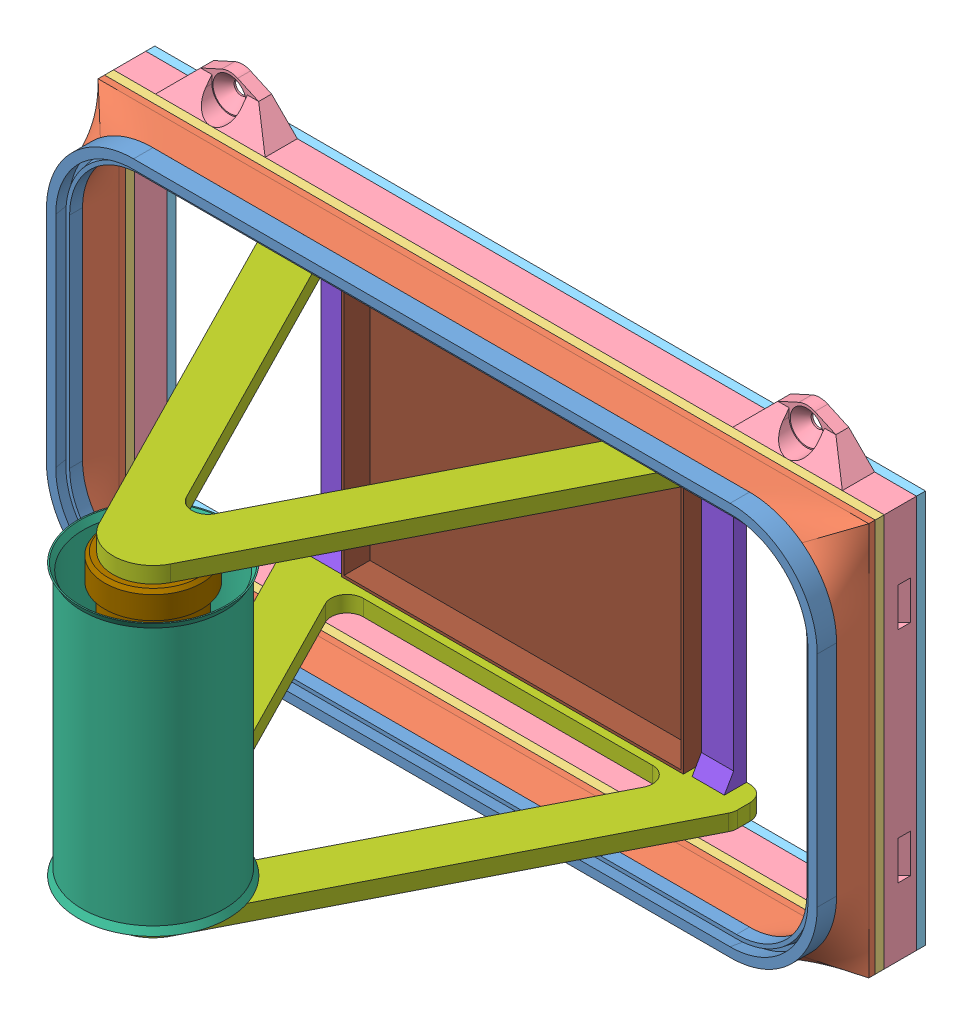
SolidWorks assembly Enclosure Filament Container, configuration Default. Lengths in mm.
Overall size (245.51 145 230).
25 component instances, 17 part files, 28 mates.
Components (placement in the parent):
- Filament Container Extension_v19.step-1: Filament Container Extension_v19.step [Default] at origin size (264.5 145 42.8)
  - Component8.step-1: Component8.step [Default] at origin size (201 111.5 39.6) (hidden)
    - CaseBot.step-1: CaseBot.step [Default] at origin size (180 107 26)
    - Axis.step-1: Axis.step [Default] at origin size (108 100 8)
    - Bearing.step-1: Bearing.step [Default] at origin size (22 7 22) (hidden)
    - Bearing.step-2: Bearing.step [Default] at (0 95 0) size (22 7 22) (hidden)
    - Bearing.step-3: Bearing.step [Default] at (-100 0 0) size (22 7 22) (hidden)
    - Bearing.step-4: Bearing.step [Default] at (-100 95 0) size (22 7 22) (hidden)
    - CaseTop.step-1: CaseTop.step [Default] at origin size (175.2 102.2 2)
  - ContainerLatch.step-1: ContainerLatch.step [Default] at origin size (239 122 6)
  - TopPiece.step-1: TopPiece.step [Default] at origin size (245.51 122 12)
  - Foam1.step-1: Foam1.step [Default] at origin size (239 122 2.8)
  - BottomPiece.step-1: BottomPiece.step [Default] at origin size (245 145 19.3)
  - Foam2.step-1: Foam2.step [Default] at origin size (239 122 2.8)
  - FrontLatch.step-1: FrontLatch.step [Default] at origin size (21.6 12 37.2) (hidden)
  - Spacer.step-1: Spacer.step [Default] at origin size (12 11.5 2.8) (hidden)
- Part48^Enclosure Filament Container-1: Part48^Enclosure Filament Container [Default] x (1 0 0) z (0 1 0) size (220 220 84) (virtual)
- Part49^Enclosure Filament Container-1: Part49^Enclosure Filament Container [Default] x (1 0 0) z (0 1 0) size (140 132.4 50) (virtual)
- Part49^Enclosure Filament Container-3: Part49^Enclosure Filament Container [Default] x (-1 0 0) z (0 -1 0) size (140 132.4 50) (virtual)
- Part52^Enclosure Filament Container-1: Part52^Enclosure Filament Container [Default] at (0 0 -28.6) x (1 0 0) z (0 0 -1) size (10 108 6.9) (virtual)
- Part52^Enclosure Filament Container-2: Part52^Enclosure Filament Container [Default] at (-118 0 -28.6) x (1 0 0) z (0 0 -1) size (10 108 6.9) (virtual)
- Part53^Enclosure Filament Container-1: Part53^Enclosure Filament Container [Default] at (0 45 0) x (-1 0 0) z (0 -1 0) size (30 30 17) (virtual)
- Part53^Enclosure Filament Container-2: Part53^Enclosure Filament Container [Default] at (0 -45 0) x (1 0 0) z (0 1 0) size (30 30 17) (virtual)
- Part54^Enclosure Filament Container-1: Part54^Enclosure Filament Container [Default] x (1 0 0) z (0 1 0) size (16.2 16.2 68) (virtual)
- Part55^Enclosure Filament Container-1: Part55^Enclosure Filament Container [Default] at origin size (106 88 8.6) (virtual)
Mates (geometry in assembly coordinates):
- InPlace1: in place: plane of ? through (0 0 0) normal (0 1 0); plane of ? through (0 0 0) normal (0 1 0); moOrthogonalPlaneRef_w of ? through (0 0 0) normal (0 1 0); plane of ? through (0 0 0) normal (0 0 -1); plane of ? through (0 0 0) normal (0 1 0); plane of ? through (0 0 0) normal (1 0 0); plane of ? through (0 0 0) normal (0 1 0); unknown of ?
- Coincident1: coincident aligned: plane of Filament Container Extension_v19.step-1; plane of Part48^Enclosure Filament Container-1
- Coincident2: coincident aligned: moOrthogonalPlaneRef_w of Filament Container Extension_v19.step-1; plane of Part48^Enclosure Filament Container-1 through (0 0 0) normal (0 0 -1)
- Coincident3: coincident anti-aligned: moOrthogonalPlaneRef_w of Filament Container Extension_v19.step-1 through (23.54 -23.54 0) axis (0 0 -1); plane of Part48^Enclosure Filament Container-1 through (0 0 0) normal (1 0 0)
- InPlace2: in place: plane of ? through (0 0 0) normal (0 1 0); plane of ? through (0 0 0) normal (0 0 -1); plane of ? through (0 0 0) normal (1 0 0); unknown of ?
- Coincident4: coincident aligned: 
- Coincident5: coincident aligned: plane of Part49^Enclosure Filament Container-1 through (0 0 0) normal (0 0 -1)
- Coincident6: coincident anti-aligned: plane of Part49^Enclosure Filament Container-1 through (0 0 0) normal (1 0 0)
- InPlace3: in place: plane of ? through (0 0 0) normal (0 1 0); plane of ? through (0 0 0) normal (0 0 -1); plane of ? through (0 0 0) normal (1 0 0); unknown of ?
- Coincident7: coincident aligned: 
- Coincident8: coincident aligned: plane of Part50^Enclosure Filament Container-1 through (0 0 0) normal (0 0 -1)
- Coincident9: coincident anti-aligned: plane of Part50^Enclosure Filament Container-1 through (0 0 0) normal (1 0 0)
- InPlace5: in place: plane of ? through (0 45 -28.6) normal (0 0 -1); plane of ? through (0 0 -28.6) normal (0 0 -1); plane of ? through (0 45 -28.6) normal (0 0 -1); plane of ? through (0 0 -28.6) normal (0 1 0); plane of ? through (0 45 -28.6) normal (0 0 -1); plane of ? through (0 0 -28.6) normal (-1 0 0); plane of ? through (0 45 -28.6) normal (0 0 -1); unknown of Part52^Enclosure Filament Container-1
- Coincident13: coincident aligned: plane of Part49^Enclosure Filament Container-1; plane of Part52^Enclosure Filament Container-1
- Coincident14: coincident aligned: moOrthogonalPlaneRef_w of Part49^Enclosure Filament Container-1 through (0 0 -28.6) normal (0 -1 0); plane of Part52^Enclosure Filament Container-1 through (0 0 -28.6) normal (0 -1 0)
- Coincident15: coincident anti-aligned: moOrthogonalPlaneRef_w of Part49^Enclosure Filament Container-1 through (0 0 -28.6) normal (-1 0 0); plane of Part52^Enclosure Filament Container-1 through (0 0 -28.6) normal (1 0 0)
- InPlace6: in place: plane of ? through (0 45 0) normal (0 -1 0); plane of Part53^Enclosure Filament Container-1 through (0 45 0) normal (0 -1 0); plane of ? through (0 45 0) normal (0 -1 0); plane of Part53^Enclosure Filament Container-1 through (0 45 0) normal (0 0 -1); plane of ? through (0 45 0) normal (0 -1 0); plane of Part53^Enclosure Filament Container-1 through (0 45 0) normal (-1 0 0); plane of ? through (0 45 0) normal (0 -1 0); unknown of Part53^Enclosure Filament Container-1
- Coincident1: coincident aligned: plane of Part49^Enclosure Filament Container-1; plane of Part53^Enclosure Filament Container-1
- Coincident2: coincident aligned: moOrthogonalPlaneRef_w of Part49^Enclosure Filament Container-1 through (0 45 0) normal (0 0 -1); plane of Part53^Enclosure Filament Container-1 through (0 45 0) normal (0 0 -1)
- Coincident3: coincident anti-aligned: moOrthogonalPlaneRef_w of Part49^Enclosure Filament Container-1 through (0 45 0) normal (1 0 0); plane of Part53^Enclosure Filament Container-1 through (0 45 0) normal (-1 0 0)
- InPlace7: in place: plane of ? through (0 0 0) normal (0 1 0); plane of ? through (0 0 0) normal (0 0 -1); plane of ? through (0 0 0) normal (1 0 0); unknown of ?
- Coincident4: coincident aligned: 
- Coincident5: coincident aligned: plane of Part54^Enclosure Filament Container-1 through (0 0 0) normal (0 0 -1)
- Coincident6: coincident anti-aligned: plane of Part54^Enclosure Filament Container-1 through (0 0 0) normal (1 0 0)
- InPlace8: in place: plane of ? through (0 0 0) normal (0 0 1); plane of ? through (0 0 0) normal (0 1 0); plane of ? through (0 0 0) normal (1 0 0); unknown of ?
- Coincident7: coincident aligned: 
- Coincident8: coincident aligned: plane of Part55^Enclosure Filament Container-1 through (0 0 0) normal (0 1 0)
- Coincident9: coincident anti-aligned: plane of Part55^Enclosure Filament Container-1 through (0 0 0) normal (1 0 0)
